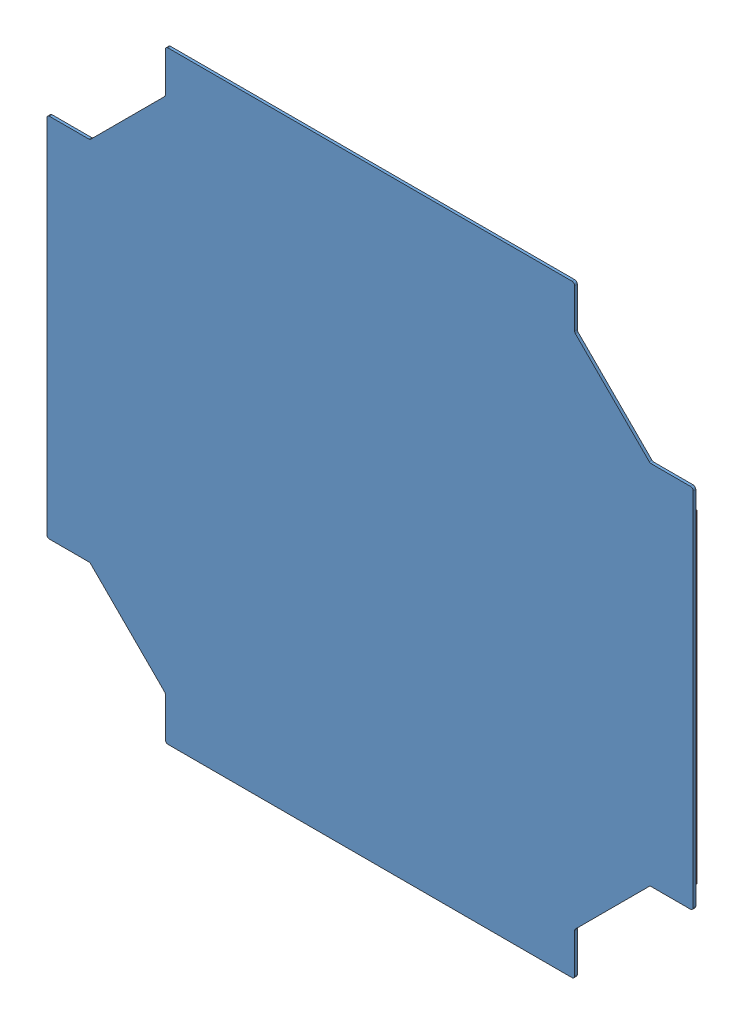
SolidWorks assembly Assem6, configuration Default. Lengths in mm.
Overall size (762 711.2 4.76).
3 component instances, 2 part files, 6 mates.
Components (placement in the parent):
- GE-20115-1: GE-20115 [Default] at (-146.255 66.0806 593.2092) size (762 711.2 3.17)
- Loop_1_15-1: Loop_1_15 [Default] at (615.745 231.1806 591.6217) x (0 1 0) z (1 0 0) size (381 1.59 25.4)
- Loop_1_15-2: Loop_1_15 [Default] at (-146.255 231.1806 593.2092) x (0 1 0) z (-1 0 0) size (381 1.59 25.4)
Mates (geometry in assembly coordinates):
- Coincident1: coincident: plane of GE-20115-1 through (-146.255 66.0806 593.2092) normal (0 0 -1); plane of Loop_1_15-1 through (-112.3374 227.2219 592.8008) normal (0 0 1)
- Coincident2: coincident: plane of GE-20115-1 through (-146.255 66.0806 593.2092) normal (0 0 -1); plane of Loop_1_15-2 through (-146.6775 231.1806 593.2092) normal (0 0 1)
- Width1: width: plane of GE-20115-1 through (-146.255 637.5806 593.2092) normal (0 1 0); plane of Loop_1_15-2 through (-146.255 205.7806 593.2092) normal (0 -1 0); plane of GE-20115-1 through (-146.6775 231.1806 591.6217) normal (0 -1 0); plane of Loop_1_15-2 through (-146.6775 612.1806 591.6217) normal (0 1 0)
- Coincident3: coincident aligned: plane of GE-20115-1 through (-146.255 66.0806 596.3842) normal (-1 0 0); plane of Loop_1_15-2 through (-146.255 231.1806 591.6217) normal (-1 0 0)
- Coincident4: coincident: plane of GE-20115-1 through (615.745 66.0806 596.3842) normal (1 0 0); plane of Loop_1_15-1 through (-112.3374 227.2219 592.8008) normal (1 0 0)
- Coincident5: coincident aligned: plane of Loop_1_15-1 through (615.745 612.1806 593.2092) normal (0 1 0); plane of Loop_1_15-2 through (-146.255 612.1806 591.6217) normal (0 1 0)
